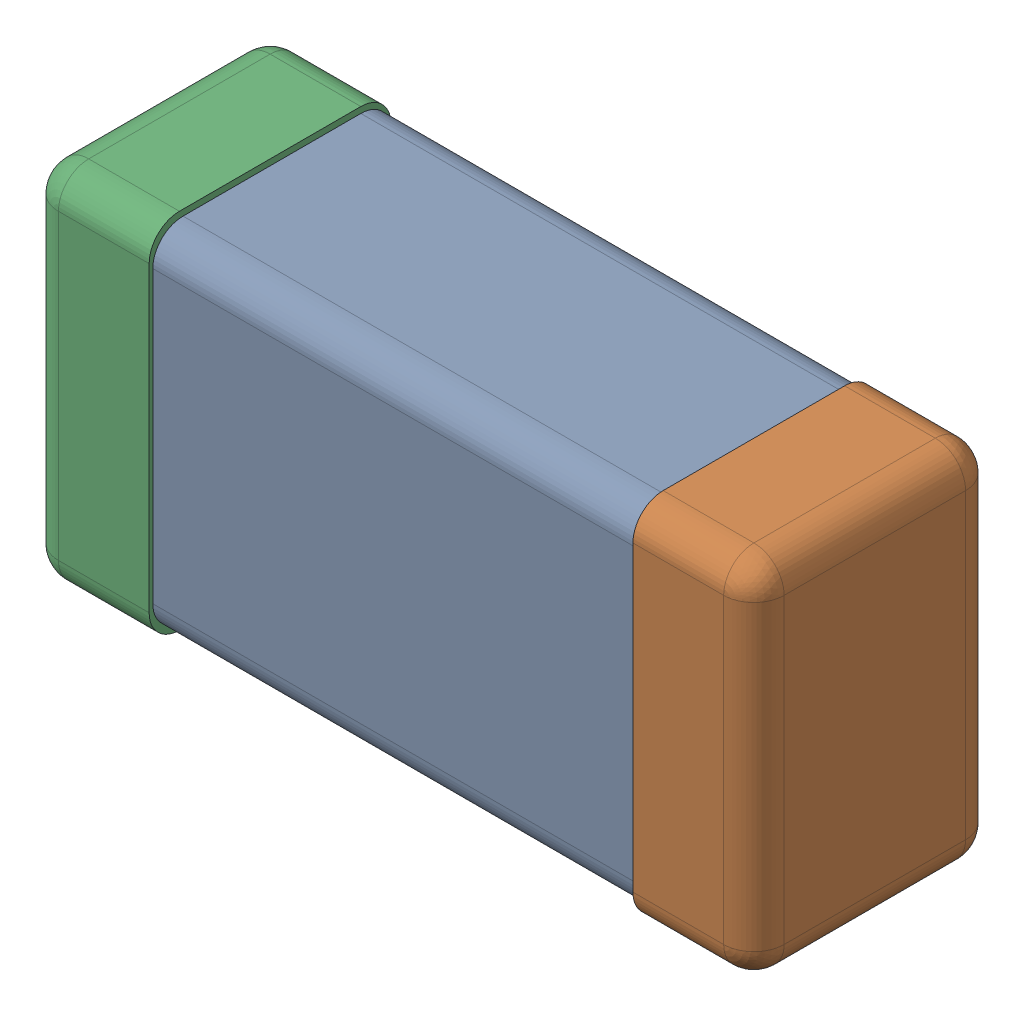
SolidWorks assembly C0201_020_27, configuration Standard. Lengths in mm.
Overall size (0.6 0.3 0.2).
3 component instances, 3 part files, 0 mates.
Components (placement in the parent):
- Part 3_2-1: Part 3_2 [Standard] at (0 0 -7.3015) size (0.5 0.29 0.2)
- Part 2_2-1: Part 2_2 [Standard] at (0 0 -7.3) size (0.1 0.3 0.2)
- Part 1_2-1: Part 1_2 [Standard] at (0 0 -7.3) size (0.1 0.3 0.2)
